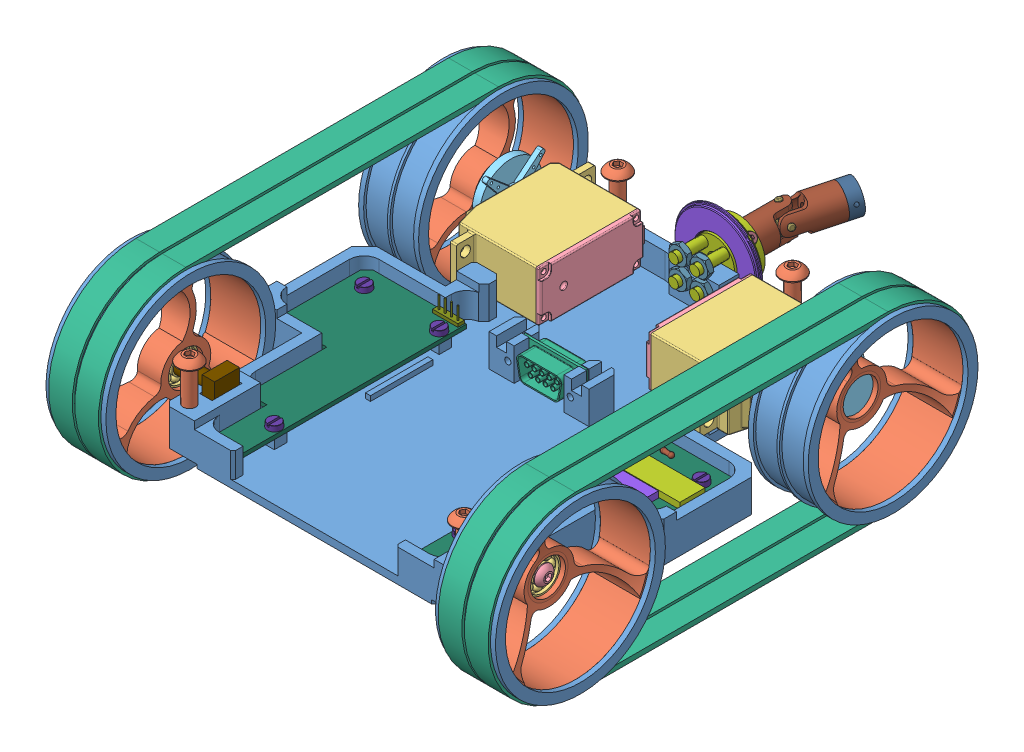
SolidWorks assembly base, configuration Default. Lengths in mm.
Overall size (180 76.51 233.06).
77 component instances, 30 part files, 77 mates.
Components (placement in the parent):
- chassi-1: chassi [Default] at origin size (160 33.25 161.25)
  - chassi_inf-1: chassi_inf [Default] at origin size (160 16 160)
  - chassi_sup-1: chassi_sup [Default] at (0 32 0) x (-1 0 0) z (0 0 1) size (160 19 160)
  - M5_25-3: M5_25 [ISO 7380 - M5 x 25 --- 25N] at (-55 33.25 75) x (0 -1 0) z (0 0 1) size (27.75 9.5 9.5)
  - M5_25-4: M5_25 [ISO 7380 - M5 x 25 --- 25N] at (55 33.25 75) x (0 -1 0) z (0 0 1) size (27.75 9.5 9.5)
  - M5_25-1: M5_25 [ISO 7380 - M5 x 25 --- 25N] at (-35 33.25 -76.5) x (0 -1 0) z (0 0 1) size (27.75 9.5 9.5)
  - M5_25-2: M5_25 [ISO 7380 - M5 x 25 --- 25N] at (35 33.25 -76.5) x (0 -1 0) z (0 0 1) size (27.75 9.5 9.5)
- FUTABA_S3003-1: FUTABA_S3003 [Default] at (23 16 -52.25) x (0 0 1) z (0 1 0) size (59.88 42.1 45.25)
  - corpo-1: corpo [Default] at origin size (55.5 40 20)
  - tampa-1: tampa [Default] x (-1 0 0) z (0 -1 0) size (43 20 2.1)
  - FUTM2040-1: FUTM2040 [Default] at (-9.5 38 0) x (-0.703172 0 0.71102) z (0 1 0) size (32 32 2)
- FUTABA_S3003-2: FUTABA_S3003 [Default] at (-23 16 -52.25) x (0 0 1) z (0 -1 0) size (59.88 42.1 45.25)
  - corpo-1: corpo [Default] at origin size (55.5 40 20)
  - tampa-1: tampa [Default] x (-1 0 0) z (0 -1 0) size (43 20 2.1)
  - FUTM2040-1: FUTM2040 [Default] at (-9.5 38 0) x (-0.703172 0 0.71102) z (0 1 0) size (32 32 2)
- SUB9_femea-1: SUB9_femea [Default] at (0 9.5 -17) size (31 12.5 11.5)
- acoplamento-1: acoplamento [Default] at (0 16 -84.5) x (-0.707107 0.707107 0) z (0 0 -1) size (34.96 34.93 63.37)
  - fixo2-1: fixo2 [Default] at origin size (29.91 29.91 21.5)
  - rotativo2-1: rotativo2 [Default] at (0 0 -3) x (-0.999922 0.012464 0) z (-0.012464 -0.999922 0) size (34.53 2 34.5)
  - Needle Rollers Thrust Bearing_SKF-1: Needle Rollers Thrust Bearing_SKF [SKF - AXK 1730 - 20,DE,AC,20] at (0 0 -2) x (0 0 -1) z (1 0 0) size (2 30 30)
  - encaixe-1: encaixe [Default] at (0 0 2.5) x (0 -1 0) z (-1 0 0) size (12.5 15 12.5)
  - encaixe-2: encaixe [Default] at (-3.92 5.989 42.2098) x (0.456781 -0.818516 0.3484) z (0.868785 0.494653 0.02307) size (12.5 15 12.5)
  - capa-1: capa [Default] at (0 0 5) x (-0.855583 -0.517666 0) z (-0.517666 0.855583 0) size (12.5 21.5 12.5)
  - capa-2: capa [Default] at (-3.442 5.2586 39.8671) x (-0.485122 0.801795 -0.348971) z (-0.853283 -0.52132 -0.011592) size (12.5 21.5 12.5)
  - elo-1: elo [Default] at (-0.542 0.8957 25.8114) x (-0.485122 0.801795 -0.348971) z (-0.855583 -0.517666 0) size (14 6 14)
  - Socket Head Cap Screw_ISO-1: Socket Head Cap Screw_ISO [ISO 4762 M2 x 6 --- 6N] at (0 11.6 2.5) x (0 -1 0) z (0 0 1) size (8 3.8 3.8)
  - Socket Head Cap Screw_ISO-2: Socket Head Cap Screw_ISO [ISO 4762 M2 x 6 --- 6N] at (11.6 0 2.5) x (-1 0 0) z (0 0.924225 0.381849) size (8 3.8 3.8)
- Hex Thin Nut Chamfered GradeAB_ISO-1: Hex Thin Nut Chamfered GradeAB_ISO [Hexagon Thin Nut ISO - 4035 - M4 - N] at (-4.2426 11.7574 -69.8) x (0.999787 0.020617 0) z (0 0 1) size (7 8.08 2.2)
- Hex Thin Nut Chamfered GradeAB_ISO-2: Hex Thin Nut Chamfered GradeAB_ISO [Hexagon Thin Nut ISO - 4035 - M4 - N] at (-4.2426 20.2426 -69.8) size (7 8.08 2.2)
- Hex Thin Nut Chamfered GradeAB_ISO-3: Hex Thin Nut Chamfered GradeAB_ISO [Hexagon Thin Nut ISO - 4035 - M4 - N] at (4.2426 20.2426 -69.8) x (-0.045816 -0.99895 0) z (0 0 1) size (7 8.08 2.2)
- Hex Thin Nut Chamfered GradeAB_ISO-4: Hex Thin Nut Chamfered GradeAB_ISO [Hexagon Thin Nut ISO - 4035 - M4 - N] at (4.2426 11.7574 -69.8) x (-0.913637 0.40653 0) z (0 0 1) size (7 8.08 2.2)
- Circuito_base_1-1: Circuito_base_1 [Default] at (-54.5 7 20.5) size (40 7.95 90)
  - PCB-1: PCB [Default] at origin size (40 1.6 90)
  - conector_4pinos_macho-1: conector_4pinos_macho [Default] at (14.3522 1.6 -34.3489) size (10.16 7.62 2.54)
- M3_nylon-1: M3_nylon [ISO 1207 - M3 x 5 --- 5N] at (-37.5 10.6 58.5) x (0 -1 0) z (0 0 1) size (7.01 5.5 5.5)
- M3_nylon-2: M3_nylon [ISO 1207 - M3 x 5 --- 5N] at (-37.5 10.6 -7.5) x (0 -1 0) z (0 0 1) size (7.01 5.5 5.5)
- M3_nylon-3: M3_nylon [ISO 1207 - M3 x 5 --- 5N] at (-67.5 10.6 -7.5) x (0 -1 0) z (0 0 1) size (7.01 5.5 5.5)
- eixo_roda-1: eixo_roda [Default] at (56.5 16 63.43) x (0 0 -1) z (1 0 0) size (10 12 23.5)
- eixo_roda-2: eixo_roda [Default] at (-56.5 16 63.43) x (0 0 1) z (-1 0 0) size (10 12 23.5)
- jante-1: jante [Default] at (-78 16 63.43) x (0 -0.134257 0.990947) z (-1 0 0) size (68 68 24)
  - aro-1: aro [Default] at origin size (68 68 24)
  - jante3-1: jante3 [Default] at (0 0 -10) size (64 64 21.3)
- jante-2: jante [Default] at (78 16 63.43) x (0 0 -1) z (1 0 0) size (68 68 24)
  - aro-1: aro [Default] at origin size (68 68 24)
  - jante3-1: jante3 [Default] at (0 0 -10) size (64 64 21.3)
- Angular Contact Ball Bearing_68_ISO-1: Angular Contact Ball Bearing_68_ISO [ISO 15 ABB - 025 - 8,DE,NC,8_68] at (-72.5 16 63.43) size (5 16 16)
- Angular Contact Ball Bearing_68_ISO-2: Angular Contact Ball Bearing_68_ISO [ISO 15 ABB - 025 - 8,DE,NC,8_68] at (72.5 16 63.43) size (5 16 16)
- Socket Button Head Screw_ISO-2: Socket Button Head Screw_ISO [ISO 7380 - M4 x 8 --- 8N] at (-77.2 16 63.43) size (10.2 7.6 7.6)
- Socket Button Head Screw_ISO-3: Socket Button Head Screw_ISO [ISO 7380 - M4 x 8 --- 8N] at (77.2 16 63.43) x (-1 0 0) z (0 0.924225 0.381849) size (10.2 7.6 7.6)
- servo_roda-1: servo_roda [Default] at (70 16 -61.75) x (0 0.703172 0.71102) z (1 0 0) size (25 25 12)
- servo_roda-2: servo_roda [Default] at (-70 16 -61.75) x (0 -0.71102 -0.703172) z (-1 0 0) size (25 25 12)
- jante-5: jante [Default] at (78 16 -61.75) x (0 0 -1) z (1 0 0) size (68 68 24)
  - aro-1: aro [Default] at origin size (68 68 24)
  - jante3-1: jante3 [Default] at (0 0 -10) size (64 64 21.3)
- jante-6: jante [Default] at (-78 16 -61.75) x (0 0 1) z (-1 0 0) size (68 68 24)
  - aro-1: aro [Default] at origin size (68 68 24)
  - jante3-1: jante3 [Default] at (0 0 -10) size (64 64 21.3)
- lagarta1-1: lagarta1 [Default] at (83.25 16 -61.75) x (0 0 -1) z (1 0 0) size (195.18 70 9.5)
- lagarta1-2: lagarta1 [Default] at (-72.75 16 -61.75) x (0 0 -1) z (1 0 0) size (195.18 70 9.5)
- lagarta1-3: lagarta1 [Default] at (-83.25 16 -61.75) x (0 0 -1) z (1 0 0) size (195.18 70 9.5)
- lagarta1-4: lagarta1 [Default] at (72.75 16 63.43) x (0 0 1) z (-1 0 0) size (195.18 70 9.5)
- Circuito_base_2-1: Circuito_base_2 [Default] at (54.5 8.6 20.5) x (-1 0 0) z (0 0 1) size (40 10.34 90)
  - PCB-1: PCB [Default] at origin size (40 1.6 90)
  - conector_4pinos_macho-1: conector_4pinos_macho [Default] at (13.9047 0 -33.8557) x (-1 0 0) z (0 0 1) size (10.16 7.62 2.54)
  - PID_28pinos_DIP-1: PID_28pinos_DIP [Default] at (-0.2707 -2.54 -19.3761) size (35.56 2.54 10.16)
  - PID_28pinos_SUP-1: PID_28pinos_SUP [Default] at (-7.0958 -8.7373 -4.0042) size (17.78 2.54 7.62)
  - condensador-1: condensador [Default] at (3.8139 -7.62 15.1376) size (3 7.62 3)
  - condensador-2: condensador [Default] at (3.8139 -7.62 10.0576) size (3 7.62 3)
  - condensador-3: condensador [Default] at (3.8139 -7.62 4.9776) size (3 7.62 3)
  - cristal-1: cristal [Default] at (12.2014 -7.62 -3.9768) size (10.16 7.62 5.08)
  - resistência-1: resistência [Default] at (8.7803 -0.9955 3.2874) x (-0.035624 0 0.999365) z (-0.273187 0.961912 -0.009738) size (5.08 1.99 1.99)
  - resistência-2: resistência [Default] at (3.1601 -0.9955 -30.5569) x (0.999654 0 -0.026292) z (0.026255 -0.052976 0.998251) size (5.08 1.99 1.99)
  - resistência-3: resistência [Default] at (11.949 -4.8167 -8.7538) size (5.08 1.99 1.99)
  - resistência-4: resistência [Default] at (3.5822 -0.9955 21.6747) x (0.007433 0 -0.999972) z (0.627842 -0.778327 0.004667) size (5.08 1.99 1.99)
- M3_nylon-4: M3_nylon [ISO 1207 - M3 x 5 --- 5N] at (67.5 10.6 -7.5) x (0 -1 0) z (0 0 1) size (7.01 5.5 5.5)
- M3_nylon-5: M3_nylon [ISO 1207 - M3 x 5 --- 5N] at (37.5 10.6 -7.5) x (0 -1 0) z (0 0 1) size (7.01 5.5 5.5)
- M3_nylon-6: M3_nylon [ISO 1207 - M3 x 5 --- 5N] at (37.5 10.6 58.5) x (0 -1 0) z (0 0 1) size (7.01 5.5 5.5)
Mates (geometry in assembly coordinates):
- Concentric2: concentric anti-aligned: cylinder of chassi-1/chassi_sup-1; cylinder of FUTABA_S3003-1/corpo-1
- Concentric3: concentric anti-aligned: cylinder of chassi-1/chassi_inf-1; cylinder of FUTABA_S3003-1/corpo-1
- Coincident2: coincident anti-aligned: plane of chassi-1/chassi_sup-1 through (47.5 29 -80) normal (1 0 0); plane of FUTABA_S3003-1/corpo-1 through (47.5 25 -24.5) normal (-1 0 0)
- Coincident3: coincident anti-aligned: plane of chassi-1/chassi_sup-1 through (-47.5 29 -80) normal (-1 0 0); plane of FUTABA_S3003-2/corpo-1 through (-47.5 7 -24.5) normal (1 0 0)
- Concentric4: concentric anti-aligned: cylinder of chassi-1/chassi_sup-1; cylinder of FUTABA_S3003-2/corpo-1
- Concentric5: concentric anti-aligned: cylinder of chassi-1/chassi_inf-1; cylinder of FUTABA_S3003-2/corpo-1
- Coincident4: coincident anti-aligned: plane of chassi-1/chassi_inf-1 through (-15.5 -28.0161 -16) normal (0 0 -1); plane of SUB9_femea-1 through (-15.5 3.25 -16) normal (0 0 1)
- Concentric6: concentric aligned: cylinder of chassi-1/chassi_inf-1; cylinder of SUB9_femea-1
- Concentric7: concentric aligned: cylinder of chassi-1/chassi_inf-1; cylinder of SUB9_femea-1
- Concentric9: concentric anti-aligned: cylinder of chassi-1/chassi_inf-1; cylinder of acoplamento-1/fixo2-1
- Concentric101: concentric aligned: unknown of acoplamento-1/fixo2-1
- Coincident61: coincident anti-aligned: unknown of chassi-1/chassi_sup-1
- Concentric111: concentric anti-aligned: unknown of chassi-1/chassi_sup-1
- Coincident71: coincident anti-aligned: unknown of chassi-1/chassi_sup-1
- Concentric121: concentric aligned: unknown of acoplamento-1/fixo2-1
- Coincident81: coincident anti-aligned: unknown of chassi-1/chassi_inf-1
- Concentric131: concentric aligned: unknown of acoplamento-1/fixo2-1
- Coincident91: coincident anti-aligned: unknown of chassi-1/chassi_inf-1
- Coincident101: coincident anti-aligned: plane of chassi-1/chassi_inf-1 through (-47.5 3 -80) normal (0 0 -1); plane of acoplamento-1/fixo2-1 through (0 16 -80) normal (0 0 1)
- Concentric151: concentric anti-aligned: cylinder of chassi-1/chassi_inf-1; cylinder of acoplamento-1/fixo2-1
- Coincident102: coincident anti-aligned: plane of chassi-1/chassi_inf-1 through (-40 7 56) normal (0 1 0); plane of Circuito_base_1-1/PCB-1 through (-74.5 7 20.5) normal (0 -1 0)
- Concentric152: concentric aligned: cylinder of chassi-1/chassi_inf-1; cylinder of Circuito_base_1-1/PCB-1
- Concentric153: concentric aligned: cylinder of chassi-1/chassi_inf-1; cylinder of Circuito_base_1-1/PCB-1
- Coincident1031: coincident anti-aligned: unknown of Circuito_base_1-1/PCB-1
- Concentric1541: concentric aligned: unknown of Circuito_base_1-1/PCB-1
- Coincident1041: coincident anti-aligned: unknown of Circuito_base_1-1/PCB-1
- Concentric1551: concentric aligned: unknown of Circuito_base_1-1/PCB-1
- Coincident1051: coincident anti-aligned: unknown of Circuito_base_1-1/PCB-1
- Coincident106: coincident anti-aligned: unknown of Circuito_base_1-1/PCB-1
- Concentric156: concentric aligned: unknown of Circuito_base_1-1/PCB-1
- Concentric157: concentric anti-aligned: cylinder of chassi-1/chassi_inf-1; cylinder of eixo_roda-1
- Concentric158: concentric anti-aligned: cylinder of chassi-1/chassi_inf-1; cylinder of eixo_roda-2
- Coincident107: coincident anti-aligned: plane of chassi-1/chassi_inf-1 through (-56.5 16 63.43) normal (1 0 0); plane of eixo_roda-2 through (-56.5 10 68.43) normal (-1 0 0)
- Coincident108: coincident anti-aligned: plane of chassi-1/chassi_inf-1 through (56.5 16 63.43) normal (-1 0 0); plane of eixo_roda-1 through (56.5 10 58.43) normal (1 0 0)
- Concentric160: concentric anti-aligned: unknown of eixo_roda-1
- Coincident110: coincident anti-aligned: unknown of eixo_roda-1
- Concentric161: concentric aligned: unknown of eixo_roda-2
- Coincident111: coincident anti-aligned: unknown of eixo_roda-2
- Concentric162: concentric aligned: unknown of jante-1/jante3-1
- Coincident112: coincident anti-aligned: unknown of jante-1/jante3-1
- Concentric163: concentric anti-aligned: unknown of jante-2/jante3-1
- Coincident113: coincident anti-aligned: unknown of jante-2/jante3-1
- Concentric1641: concentric aligned: unknown of eixo_roda-2
- Coincident1141: coincident anti-aligned: unknown of eixo_roda-2
- Concentric1651: concentric aligned: unknown of eixo_roda-1
- Coincident1151: coincident anti-aligned: unknown of eixo_roda-1
- Coincident1159: coincident anti-aligned: plane of FUTABA_S3003-2/FUTM2040-1 through (-63 16 -61.75) normal (-1 0 0); plane of servo_roda-2 through (-63 16 -61.75) normal (1 0 0)
- Coincident1160: coincident anti-aligned: plane of FUTABA_S3003-2/FUTM2040-1 through (-63 16 -61.75) normal (-1 0 0); plane of servo_roda-2 through (-63 16 -61.75) normal (1 0 0)
- Coincident1161: coincident anti-aligned: plane of FUTABA_S3003-1/FUTM2040-1 through (63 16 -61.75) normal (1 0 0); plane of servo_roda-1 through (63 16 -61.75) normal (-1 0 0)
- Concentric1661: concentric anti-aligned: cylinder of FUTABA_S3003-1/FUTM2040-1; cylinder of servo_roda-1
- Concentric1662: concentric aligned: cylinder of FUTABA_S3003-1/FUTM2040-1; cylinder of servo_roda-1
- Coincident1162: coincident anti-aligned: plane of FUTABA_S3003-2/FUTM2040-1 through (-63 16 -61.75) normal (-1 0 0); plane of servo_roda-2 through (-63 16 -61.75) normal (1 0 0)
- Concentric1663: concentric aligned: cylinder of FUTABA_S3003-2/FUTM2040-1; cylinder of servo_roda-2
- Concentric1664: concentric aligned: cylinder of FUTABA_S3003-2/FUTM2040-1; cylinder of servo_roda-2
- Concentric1665: concentric aligned: cylinder of servo_roda-2; cylinder of jante-6/jante3-1
- Coincident1163: coincident anti-aligned: plane of servo_roda-2 through (-75 16 -61.75) normal (-1 0 0); plane of jante-6/jante3-1 through (-75 16 -61.75) normal (1 0 0)
- Concentric1666: concentric aligned: cylinder of servo_roda-1; cylinder of jante-5/jante3-1
- Coincident1164: coincident anti-aligned: plane of servo_roda-1 through (70 16 -61.75) normal (-1 0 0); plane of jante-5/jante3-1 through (70 16 -61.75) normal (1 0 0)
- BeltMate1: belt = 66 mm: cylinder of jante-5/aro-1; cylinder of jante-2/aro-1
- Concentric1667: concentric anti-aligned: cylinder of jante-2/aro-1; cylinder of lagarta1-4
- Concentric1668: concentric anti-aligned: cylinder of jante-5/aro-1; cylinder of lagarta1-4
- Coincident1165: coincident anti-aligned: plane of jante-5/aro-1 through (77.5 16 -94.75) normal (-1 0 0); plane of lagarta1-4 through (77.5 16 63.43) normal (1 0 0)
- Concentric1669: concentric anti-aligned: cylinder of jante-1/aro-1; cylinder of lagarta1-3
- Concentric1670: concentric anti-aligned: cylinder of jante-1/aro-1; cylinder of lagarta1-2
- Coincident1166: coincident anti-aligned: plane of jante-1/aro-1 through (-78.5 11.5695 96.1312) normal (-1 0 0); plane of lagarta1-3 through (-78.5 16 -61.75) normal (1 0 0)
- Coincident1167: coincident anti-aligned: plane of jante-1/aro-1 through (-68 11.5695 96.1312) normal (-1 0 0); plane of lagarta1-2 through (-68 16 -61.75) normal (1 0 0)
- Concentric1671: concentric anti-aligned: cylinder of jante-6/aro-1; cylinder of lagarta1-3
- Concentric1672: concentric anti-aligned: cylinder of jante-6/aro-1; cylinder of lagarta1-2
- Coincident1168: coincident anti-aligned: plane of chassi-1/chassi_inf-1 through (35 7 -10) normal (0 1 0); plane of Circuito_base_2-1/PCB-1 through (74.5 7 20.5) normal (0 -1 0)
- Concentric1673: concentric anti-aligned: cylinder of chassi-1/chassi_inf-1; cylinder of Circuito_base_2-1/PCB-1
- Concentric1674: concentric anti-aligned: cylinder of chassi-1/chassi_inf-1; cylinder of Circuito_base_2-1/PCB-1
- Concentric1675: concentric anti-aligned: unknown of Circuito_base_2-1/PCB-1
- Concentric1676: concentric anti-aligned: unknown of Circuito_base_2-1/PCB-1
- Concentric1677: concentric anti-aligned: unknown of Circuito_base_2-1/PCB-1
- Coincident1169: coincident anti-aligned: unknown of Circuito_base_2-1/PCB-1
- Coincident1170: coincident anti-aligned: unknown of Circuito_base_2-1/PCB-1
- Coincident1171: coincident anti-aligned: unknown of Circuito_base_2-1/PCB-1
